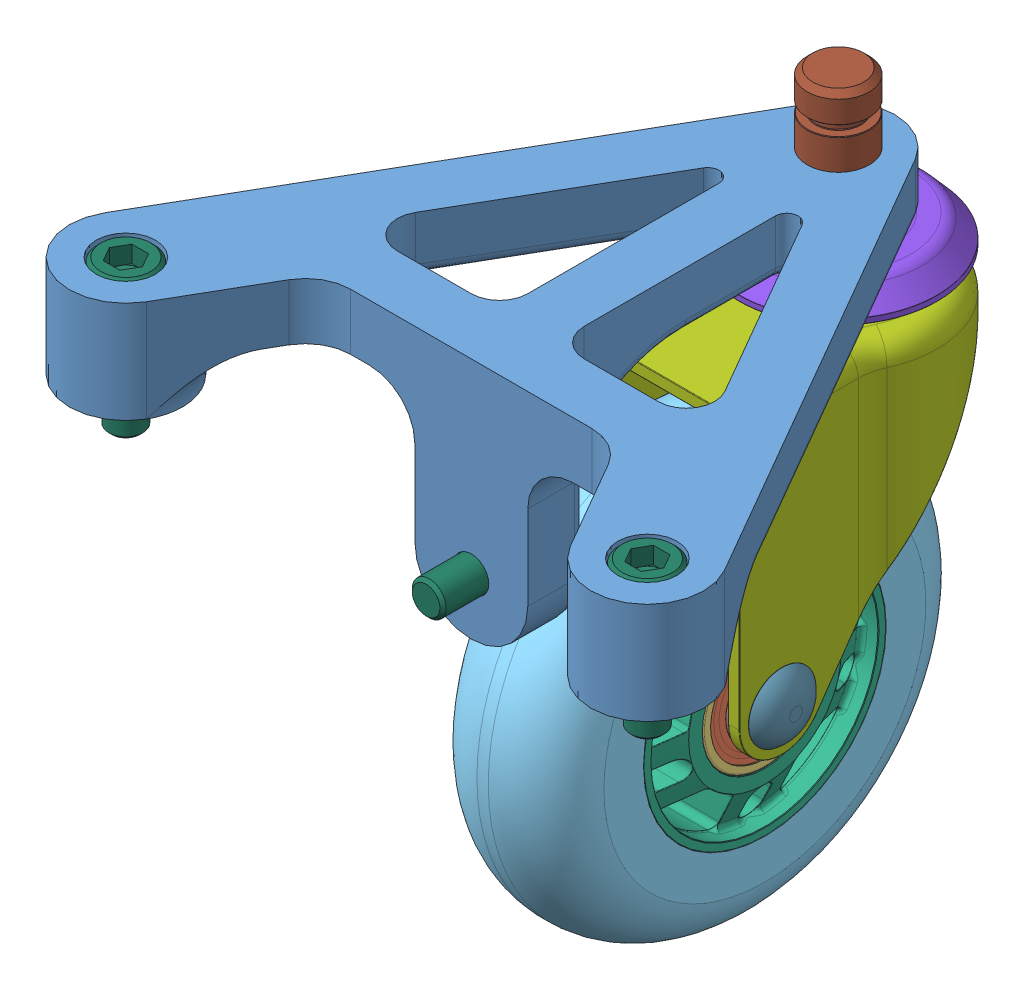
SolidWorks assembly front-wheel-center, configuration Default. Lengths in mm.
Overall size (112.38 103.75 107.5).
50 component instances, 15 part files, 9 mates.
Components (placement in the parent):
- front-wheel-center-mount-1: front-wheel-center-mount [Default] at origin size (112.38 43 100)
- caster-wheel-1: caster-wheel [Default] at (0 -55.75 -55) x (0 0 1) z (-1 0 0) size (80.5 103.75 35.8)
  - OCW_00(2)^caster-wheel-1: OCW_00(2)^caster-wheel [Default] at origin size (80.5 103.75 35.8) (virtual)
    - SKF_608-2Z^OCW_00(2)_caster-wheel-1: SKF_608-2Z^OCW_00(2)_caster-wheel [Default] at (0 0 12) x (0 0 -1) z (-0.332817 0.942991 0) size (7 22 22) (virtual)
      - SKF_608-2Z_PART1^SKF_608-2Z_OCW_00(2)_caster-wheel-1: SKF_608-2Z_PART1^SKF_608-2Z_OCW_00(2)_caster-wheel [Default] at origin size (7 19.2 19.2) (virtual)
      - SKF_608-2Z_PART2^SKF_608-2Z_OCW_00(2)_caster-wheel-1: SKF_608-2Z_PART2^SKF_608-2Z_OCW_00(2)_caster-wheel [Default] at origin size (7 22 22) (virtual)
      - SKF_608-2Z_PART3^SKF_608-2Z_OCW_00(2)_caster-wheel-1: SKF_608-2Z_PART3^SKF_608-2Z_OCW_00(2)_caster-wheel [Default] at origin size (3.97 3.97 3.97) (virtual)
      - SKF_608-2Z_PART3^SKF_608-2Z_OCW_00(2)_caster-wheel-2: SKF_608-2Z_PART3^SKF_608-2Z_OCW_00(2)_caster-wheel [Default] x (1 0 0) z (0 0.781831 0.62349) size (3.97 3.97 3.97) (virtual)
      - SKF_608-2Z_PART3^SKF_608-2Z_OCW_00(2)_caster-wheel-3: SKF_608-2Z_PART3^SKF_608-2Z_OCW_00(2)_caster-wheel [Default] x (1 0 0) z (0 0.974928 -0.222521) size (3.97 3.97 3.97) (virtual)
      - SKF_608-2Z_PART3^SKF_608-2Z_OCW_00(2)_caster-wheel-4: SKF_608-2Z_PART3^SKF_608-2Z_OCW_00(2)_caster-wheel [Default] x (1 0 0) z (0 0.433884 -0.900969) size (3.97 3.97 3.97) (virtual)
      - SKF_608-2Z_PART3^SKF_608-2Z_OCW_00(2)_caster-wheel-5: SKF_608-2Z_PART3^SKF_608-2Z_OCW_00(2)_caster-wheel [Default] x (1 0 0) z (0 -0.433884 -0.900969) size (3.97 3.97 3.97) (virtual)
      - SKF_608-2Z_PART3^SKF_608-2Z_OCW_00(2)_caster-wheel-6: SKF_608-2Z_PART3^SKF_608-2Z_OCW_00(2)_caster-wheel [Default] x (1 0 0) z (0 -0.974928 -0.222521) size (3.97 3.97 3.97) (virtual)
      - SKF_608-2Z_PART3^SKF_608-2Z_OCW_00(2)_caster-wheel-7: SKF_608-2Z_PART3^SKF_608-2Z_OCW_00(2)_caster-wheel [Default] x (1 0 0) z (0 -0.781831 0.62349) size (3.97 3.97 3.97) (virtual)
    - SKF_608-2Z^OCW_00(2)_caster-wheel-2: SKF_608-2Z^OCW_00(2)_caster-wheel [Default] at (0 0 -5) x (0 0 -1) z (-0.040558 0.999177 0) size (7 22 22) (virtual)
      - SKF_608-2Z_PART1^SKF_608-2Z_OCW_00(2)_caster-wheel-1: SKF_608-2Z_PART1^SKF_608-2Z_OCW_00(2)_caster-wheel [Default] at origin size (7 19.2 19.2) (virtual)
      - SKF_608-2Z_PART2^SKF_608-2Z_OCW_00(2)_caster-wheel-1: SKF_608-2Z_PART2^SKF_608-2Z_OCW_00(2)_caster-wheel [Default] at origin size (7 22 22) (virtual)
      - SKF_608-2Z_PART3^SKF_608-2Z_OCW_00(2)_caster-wheel-1: SKF_608-2Z_PART3^SKF_608-2Z_OCW_00(2)_caster-wheel [Default] at origin size (3.97 3.97 3.97) (virtual)
      - SKF_608-2Z_PART3^SKF_608-2Z_OCW_00(2)_caster-wheel-2: SKF_608-2Z_PART3^SKF_608-2Z_OCW_00(2)_caster-wheel [Default] x (1 0 0) z (0 0.781831 0.62349) size (3.97 3.97 3.97) (virtual)
      - SKF_608-2Z_PART3^SKF_608-2Z_OCW_00(2)_caster-wheel-3: SKF_608-2Z_PART3^SKF_608-2Z_OCW_00(2)_caster-wheel [Default] x (1 0 0) z (0 0.974928 -0.222521) size (3.97 3.97 3.97) (virtual)
      - SKF_608-2Z_PART3^SKF_608-2Z_OCW_00(2)_caster-wheel-4: SKF_608-2Z_PART3^SKF_608-2Z_OCW_00(2)_caster-wheel [Default] x (1 0 0) z (0 0.433884 -0.900969) size (3.97 3.97 3.97) (virtual)
      - SKF_608-2Z_PART3^SKF_608-2Z_OCW_00(2)_caster-wheel-5: SKF_608-2Z_PART3^SKF_608-2Z_OCW_00(2)_caster-wheel [Default] x (1 0 0) z (0 -0.433884 -0.900969) size (3.97 3.97 3.97) (virtual)
      - SKF_608-2Z_PART3^SKF_608-2Z_OCW_00(2)_caster-wheel-6: SKF_608-2Z_PART3^SKF_608-2Z_OCW_00(2)_caster-wheel [Default] x (1 0 0) z (0 -0.974928 -0.222521) size (3.97 3.97 3.97) (virtual)
      - SKF_608-2Z_PART3^SKF_608-2Z_OCW_00(2)_caster-wheel-7: SKF_608-2Z_PART3^SKF_608-2Z_OCW_00(2)_caster-wheel [Default] x (1 0 0) z (0 -0.781831 0.62349) size (3.97 3.97 3.97) (virtual)
    - OCW_01^OCW_00(2)_caster-wheel-1: OCW_01^OCW_00(2)_caster-wheel [Default] x (-1 0 0) z (0 0 1) size (76 76 24) (virtual)
    - OCW_02^OCW_00(2)_caster-wheel-1: OCW_02^OCW_00(2)_caster-wheel [Default] x (-1 0 0) z (0 0 1) size (59 59 24.01) (virtual)
    - OCW_03^OCW_00(2)_caster-wheel-1: OCW_03^OCW_00(2)_caster-wheel [Default] at (-17.5 20 0) size (50 55 35.8) (virtual)
    - OCW_05^OCW_00(2)_caster-wheel-1: OCW_05^OCW_00(2)_caster-wheel [Default] at (-25 50.75 0) size (35 5 35) (virtual)
    - OCW_04^OCW_00(2)_caster-wheel-1: OCW_04^OCW_00(2)_caster-wheel [Default] at (-13 50.75 0) x (0.335189 -0.942151 0) z (0.942151 0.335189 0) size (5 5 5) (virtual)
    - OCW_04^OCW_00(2)_caster-wheel-2: OCW_04^OCW_00(2)_caster-wheel [Default] at (-14.1884 50.75 -5.2066) x (0.301995 -0.942151 -0.145433) z (0.848849 0.335189 -0.408784) size (5 5 5) (virtual)
    - OCW_04^OCW_00(2)_caster-wheel-3: OCW_04^OCW_00(2)_caster-wheel [Default] at (-17.5181 50.75 -9.382) x (0.208987 -0.942151 -0.262061) z (0.587422 0.335189 -0.736603) size (5 5 5) (virtual)
    - OCW_04^OCW_00(2)_caster-wheel-4: OCW_04^OCW_00(2)_caster-wheel [Default] at (-22.3297 50.75 -11.6991) x (0.074587 -0.942151 -0.326785) z (0.209648 0.335189 -0.918529) size (5 5 5) (virtual)
    - OCW_04^OCW_00(2)_caster-wheel-5: OCW_04^OCW_00(2)_caster-wheel [Default] at (-27.6703 50.75 -11.6991) x (-0.074587 -0.942151 -0.326785) z (-0.209648 0.335189 -0.918529) size (5 5 5) (virtual)
    - OCW_04^OCW_00(2)_caster-wheel-6: OCW_04^OCW_00(2)_caster-wheel [Default] at (-32.4819 50.75 -9.382) x (-0.208987 -0.942151 -0.262061) z (-0.587422 0.335189 -0.736603) size (5 5 5) (virtual)
    - OCW_04^OCW_00(2)_caster-wheel-7: OCW_04^OCW_00(2)_caster-wheel [Default] at (-35.8116 50.75 -5.2066) x (-0.301995 -0.942151 -0.145433) z (-0.848849 0.335189 -0.408784) size (5 5 5) (virtual)
    - OCW_04^OCW_00(2)_caster-wheel-8: OCW_04^OCW_00(2)_caster-wheel [Default] at (-37 50.75 0) x (-0.335189 -0.942151 0) z (-0.942151 0.335189 0) size (5 5 5) (virtual)
    - OCW_04^OCW_00(2)_caster-wheel-9: OCW_04^OCW_00(2)_caster-wheel [Default] at (-35.8116 50.75 5.2066) x (-0.301995 -0.942151 0.145433) z (-0.848849 0.335189 0.408784) size (5 5 5) (virtual)
    - OCW_04^OCW_00(2)_caster-wheel-10: OCW_04^OCW_00(2)_caster-wheel [Default] at (-32.4819 50.75 9.382) x (-0.208987 -0.942151 0.262061) z (-0.587422 0.335189 0.736603) size (5 5 5) (virtual)
    - OCW_04^OCW_00(2)_caster-wheel-11: OCW_04^OCW_00(2)_caster-wheel [Default] at (-27.6703 50.75 11.6991) x (-0.074587 -0.942151 0.326785) z (-0.209648 0.335189 0.918529) size (5 5 5) (virtual)
    - OCW_04^OCW_00(2)_caster-wheel-12: OCW_04^OCW_00(2)_caster-wheel [Default] at (-22.3297 50.75 11.6991) x (0.074587 -0.942151 0.326785) z (0.209648 0.335189 0.918529) size (5 5 5) (virtual)
    - OCW_04^OCW_00(2)_caster-wheel-13: OCW_04^OCW_00(2)_caster-wheel [Default] at (-17.5181 50.75 9.382) x (0.208987 -0.942151 0.262061) z (0.587422 0.335189 0.736603) size (5 5 5) (virtual)
    - OCW_04^OCW_00(2)_caster-wheel-14: OCW_04^OCW_00(2)_caster-wheel [Default] at (-14.1884 50.75 5.2066) x (0.301995 -0.942151 0.145433) z (0.848849 0.335189 0.408784) size (5 5 5) (virtual)
    - OCW_06^OCW_00(2)_caster-wheel-1: OCW_06^OCW_00(2)_caster-wheel [Default] at (-25 47.5 0) size (24 3.25 24) (virtual)
    - OCW_07^OCW_00(2)_caster-wheel-1: OCW_07^OCW_00(2)_caster-wheel [Default] at (-25 77.95 0) size (21.02 22.8 20.41) (virtual)
    - OCW_08^OCW_00(2)_caster-wheel-1: OCW_08^OCW_00(2)_caster-wheel [Default] at (-25 45.5 0) size (24 0.99 24) (virtual)
    - OCW_10^OCW_00(2)_caster-wheel-1: OCW_10^OCW_00(2)_caster-wheel [Default] at (0 0 12.5) size (14 14 1) (virtual)
    - OCW_10^OCW_00(2)_caster-wheel-2: OCW_10^OCW_00(2)_caster-wheel [Default] at (0 0 -12.5) size (14 14 1) (virtual)
    - OCW_11^OCW_00(2)_caster-wheel-1: OCW_11^OCW_00(2)_caster-wheel [Default] at origin size (11.9 11.9 35) (virtual)
- socket head cap screw_am-1: socket head cap screw_am [B18.3.1M - 6 x 1.0 x 20 Hex SHCS -- 20NHX] at (-46.188 10 0) x (0 -1 0) z (0 0 1) size (26 10 10)
- socket head cap screw_am-2: socket head cap screw_am [B18.3.1M - 6 x 1.0 x 20 Hex SHCS -- 20NHX] at (46.188 10 0) x (0 -1 0) z (0 0 1) size (26 10 10)
- socket head cap screw_am-3: socket head cap screw_am [B18.3.1M - 6 x 1.0 x 12 Hex SHCS -- 12NHX] at (0 -23 -25) x (0 0 1) z (-1 0 0) size (18 10 10)
Mates (geometry in assembly coordinates):
- Concentric1: concentric anti-aligned: cylinder of front-wheel-center-mount-1 through (0 10 -80) axis (0 -1 0) radius 5; cylinder of caster-wheel-1/OCW_00(2)^caster-wheel-1/OCW_07^OCW_00(2)_caster-wheel-1 through (0 7.8 -80) axis (0 1 0) radius 5.5
- Coincident2: coincident anti-aligned: plane of front-wheel-center-mount-1 through (0 0 0) normal (0 -1 0); plane of caster-wheel-1/OCW_00(2)^caster-wheel-1/OCW_05^OCW_00(2)_caster-wheel-1 through (0 0 -66) normal (0 1 0)
- Concentric2: concentric anti-aligned: cylinder of front-wheel-center-mount-1 through (-46.188 10 0) axis (0 -1 0) radius 3.1; cylinder of socket head cap screw_am-1 through (-46.188 41.75 0) axis (0 1 0) radius 5
- Coincident3: coincident anti-aligned: plane of front-wheel-center-mount-1 through (-46.188 4 0) normal (0 1 0); plane of socket head cap screw_am-1 through (-41.188 4 0) normal (0 -1 0)
- Concentric3: concentric aligned: cylinder of front-wheel-center-mount-1 through (46.188 4 0) axis (0 1 0) radius 5.25; cylinder of socket head cap screw_am-2 through (46.188 41.75 0) axis (0 1 0) radius 5
- Coincident4: coincident anti-aligned: plane of front-wheel-center-mount-1 through (46.188 4 0) normal (0 1 0); plane of socket head cap screw_am-2 through (51.188 4 0) normal (0 -1 0)
- Concentric4: concentric anti-aligned: cylinder of front-wheel-center-mount-1 through (0 -23 -90.001) axis (0 0 1) radius 3.1; cylinder of socket head cap screw_am-3 through (0 -23 -56.75) axis (0 0 -1) radius 5
- Coincident5: coincident anti-aligned: plane of front-wheel-center-mount-1 through (0 -23 -19) normal (0 0 -1); plane of socket head cap screw_am-3 through (0 -18 -19) normal (0 0 1)
- Coincident6: coincident anti-aligned: plane of caster-wheel-1 through (0 -55.75 -55) normal (-1 0 0)
